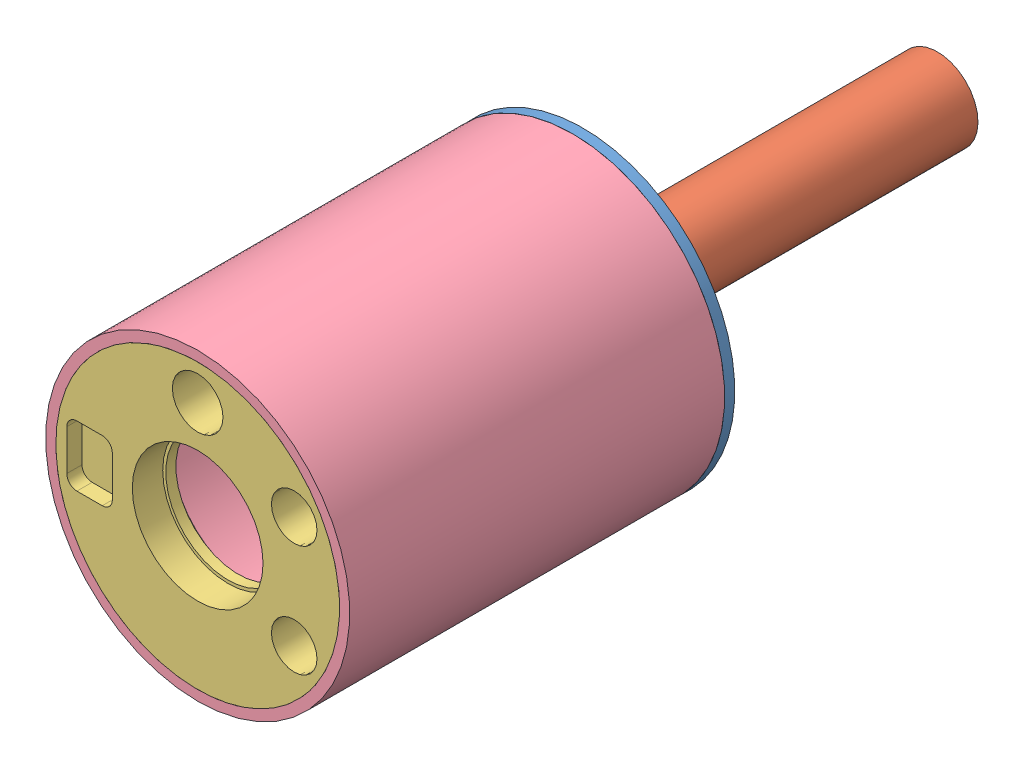
SolidWorks assembly Cavity, configuration Default. Lengths in mm.
Overall size (30 30 73.05).
4 component instances, 4 part files, 6 mates.
Components (placement in the parent):
- CavityLower_20039-20-1: CavityLower_20039-20 [Default] at origin size (30 30 5)
- CavityTail_20039-4-1: CavityTail_20039-4 [Default] at (0 0 -2) x (0.121263 0.99262 0) z (0 0 1) size (8 8 35.01)
- CavityUpper_20039-20-1: CavityUpper_20039-20 [Default] at (0 0 31) size (28.28 28 5.05)
- ChamberWalls_20061-13-1: ChamberWalls_20061-13 [Default] at (0 0 -1) x (-1 0 0) z (0 1 0) size (30 37 30)
Mates (geometry in assembly coordinates):
- Concentric1: concentric anti-aligned: circle of CavityLower_20039-20-1; circle of ChamberWalls_20061-13-1
- Concentric2: concentric anti-aligned: circle of CavityLower_20039-20-1; circle of CavityTail_20039-4-1
- Concentric3: concentric aligned: circle of CavityUpper_20039-20-1; circle of ChamberWalls_20061-13-1
- Coincident1: coincident aligned: plane of CavityUpper_20039-20-1 through (0 0 36) normal (0 0 1); plane of ChamberWalls_20061-13-1 through (0 0 36) normal (0 0 1)
- Coincident2: coincident anti-aligned: plane of CavityLower_20039-20-1 through (14 0 -1) normal (0 0 1); plane of ChamberWalls_20061-13-1 through (0 0 -1) normal (0 0 -1)
- Coincident3: coincident anti-aligned: plane of CavityLower_20039-20-1 through (15 0 -2) normal (0 0 -1); plane of CavityTail_20039-4-1 through (0 0 -2) normal (0 0 1)
